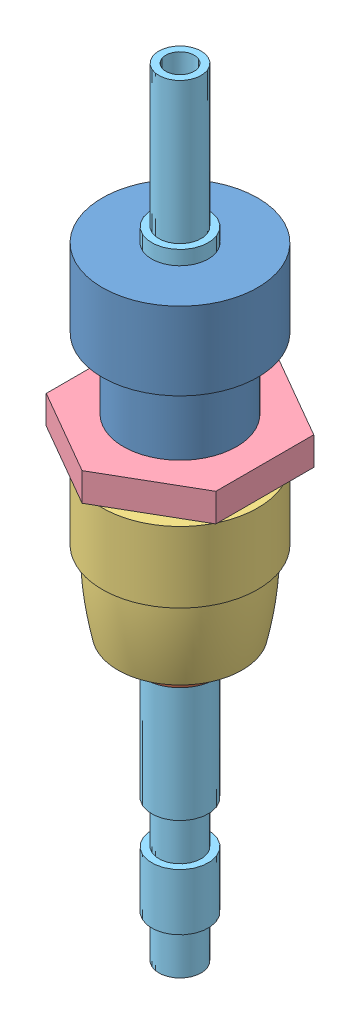
SolidWorks assembly Цанга с малой иглой, configuration По умолчанию. Lengths in mm.
Overall size (12 55 13.86).
6 component instances, 5 part files, 5 mates.
Components (placement in the parent):
- Цанговый зажим-1: Цанговый зажим [По умолчанию] x (1 0 0) z (0 0 -1) size (12 25.5 13.86)
  - втулка-1: втулка [По умолчанию] at origin size (11 20 11)
  - цанга-1: цанга [По умолчанию] at (0 10 0) size (6 15.5 6)
  - прижимная гайка-1: прижимная гайка [По умолчанию] at (0 13.5 0) x (-1 0 0) z (0 0 -1) size (11 10.5 11)
  - фиксирующая гайка-1: фиксирующая гайка [По умолчанию] at (0 12.5 0) x (1 0 0) z (0 -1 0) size (12 13.86 2)
- Игла без соска малая-1: Игла без соска малая [По умолчанию] at (0 -44 0) x (-0.583227 0 -0.812309) z (0.812309 0 -0.583227) size (4 55 4)
Mates (geometry in assembly coordinates):
- Совпадение1: coincident aligned: plane of Цанговый зажим-1/втулка-1 through (5.5 0 0) normal (0 1 0); plane of assembly through (0 0 0) normal (0 1 0)
- Совпадение2: coincident anti-aligned: plane of Цанговый зажим-1/втулка-1 through (0 0 0) normal (0 0 -1); plane of assembly through (0 0 0) normal (0 0 1)
- Совпадение3: coincident aligned: plane of Цанговый зажим-1/втулка-1; plane of assembly through (0 0 0) normal (1 0 0)
- Концентричный1: concentric anti-aligned: cylinder of Цанговый зажим-1/втулка-1 through (0 -20 0) axis (0 1 0) radius 2; cylinder of Игла без соска малая-1 through (0 11 0) axis (0 -1 0) radius 2
- Совпадение4: coincident: plane of Цанговый зажим-1/прижимная гайка-1 through (0 -24 0) normal (0 -1 0); point of Игла без соска малая-1
